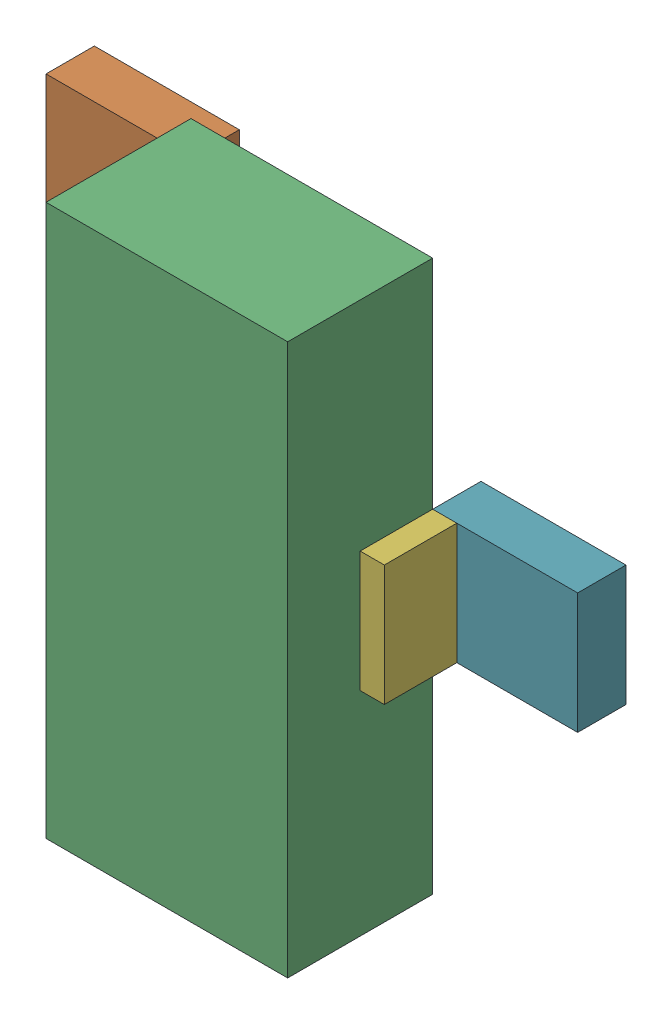
SolidWorks assembly Q1, configuration Default. Lengths in mm.
Overall size (2.79 2.9 1.02).
14 component instances, 3 part files, 0 mates.
Components (placement in the parent):
- 898052496-1: 898052496 [Default] at (35.6409 16.3393 0) size (0.76 0.64 0.25)
  - Extruded_10-1: Extruded_10 [Default] at origin size (0.76 0.64 0.25)
- 898052496-2: 898052496 [Default] at (35.6409 18.2443 0) size (0.76 0.64 0.25)
  - Extruded_10-1: Extruded_10 [Default] at origin size (0.76 0.64 0.25)
- 898052360-1: 898052360 [Default] at (36.6569 17.2918 0.254) size (1.27 2.9 0.76)
  - Extruded_11-1: Extruded_11 [Default] at origin size (1.27 2.9 0.76)
- 898052632-1: 898052632 [Default] at (35.9584 16.3393 0.254) size (0.13 0.64 0.38)
  - Extruded_12-1: Extruded_12 [Default] at origin size (0.13 0.64 0.38)
- 898052632-2: 898052632 [Default] at (35.9584 18.2443 0.254) size (0.13 0.64 0.38)
  - Extruded_12-1: Extruded_12 [Default] at origin size (0.13 0.64 0.38)
- 898052632-3: 898052632 [Default] at (37.3554 17.2791 0.254) size (0.13 0.64 0.38)
  - Extruded_12-1: Extruded_12 [Default] at origin size (0.13 0.64 0.38)
- 898052496-3: 898052496 [Default] at (37.6728 17.2791 0) size (0.76 0.64 0.25)
  - Extruded_10-1: Extruded_10 [Default] at origin size (0.76 0.64 0.25)
